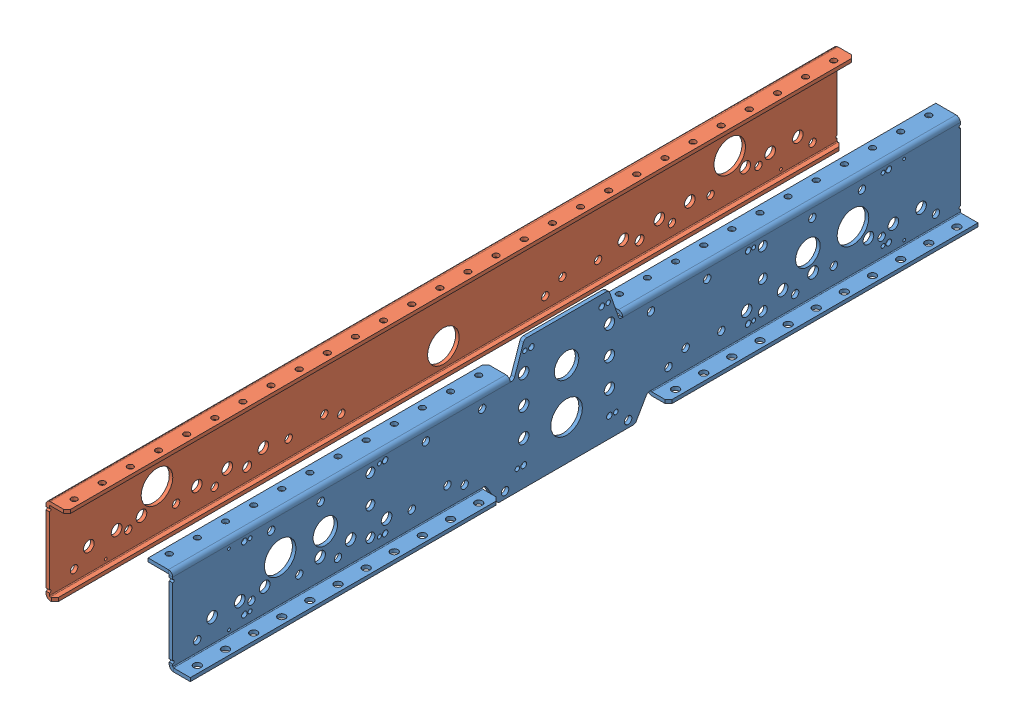
SolidWorks assembly AM14U3Square_Frame_Half, configuration Default. Lengths in mm.
Overall size (130.18 116.33 711.33).
2 component instances, 2 part files, 0 mates.
Components (placement in the parent):
- AM14U3InnerPlate_Square-1: AM14U3InnerPlate_Square [Default] at (-733.5226 -76.962 765.048) x (0 0 -1) z (0 -1 0) size (711.2 38.1 116.33)
- AM14U3OuterPlate_Square-1: AM14U3OuterPlate_Square [Default] at (-820.246 -26.7681 74.8245) x (0 0 1) z (0 -1 0) size (711.2 19.05 77.72)
